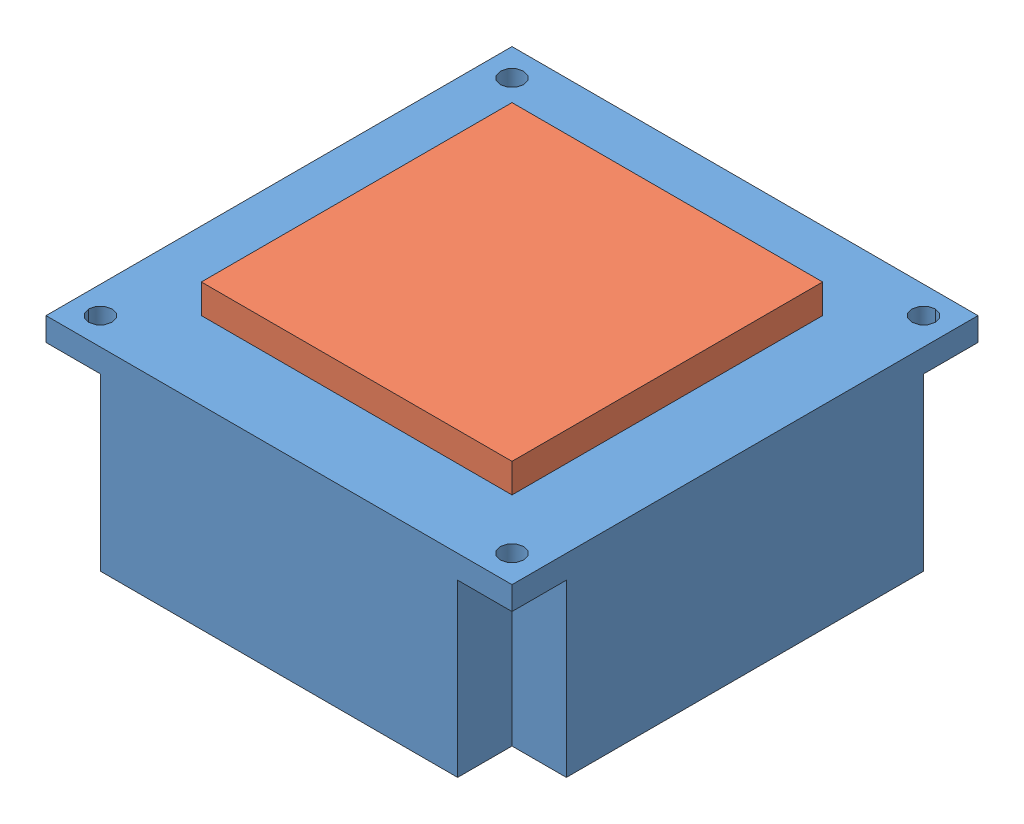
SolidWorks assembly HeatSink_Peltier, configuration Default. Lengths in mm.
Overall size (60 28.75 60).
2 component instances, 2 part files, 3 mates.
Components (placement in the parent):
- HeatSink-1: HeatSink [Default] at (-6.3433 -22.0506 -73.1894) x (1 0 0) z (0 0 -1) size (60 25 60)
- Peltier_40mm-1: Peltier_40mm [Default] at (3.6567 -18.3006 -63.1894) x (1 0 0) z (0 -1 0) size (40 40 3.75)
Mates (geometry in assembly coordinates):
- Coincident1: coincident anti-aligned: plane of HeatSink-1 through (-6.3433 -22.0506 -73.1894) normal (0 1 0); plane of Peltier_40mm-1 through (3.6567 -22.0506 -63.1894) normal (0 -1 0)
- Coincident3: coincident: point of HeatSink-1; point of Peltier_40mm-1
- Parallel1: parallel aligned: plane of HeatSink-1 through (-6.3433 -25.0506 -73.1894) normal (-1 0 0); plane of Peltier_40mm-1 through (3.6567 -22.0506 -63.1894) normal (-1 0 0)
